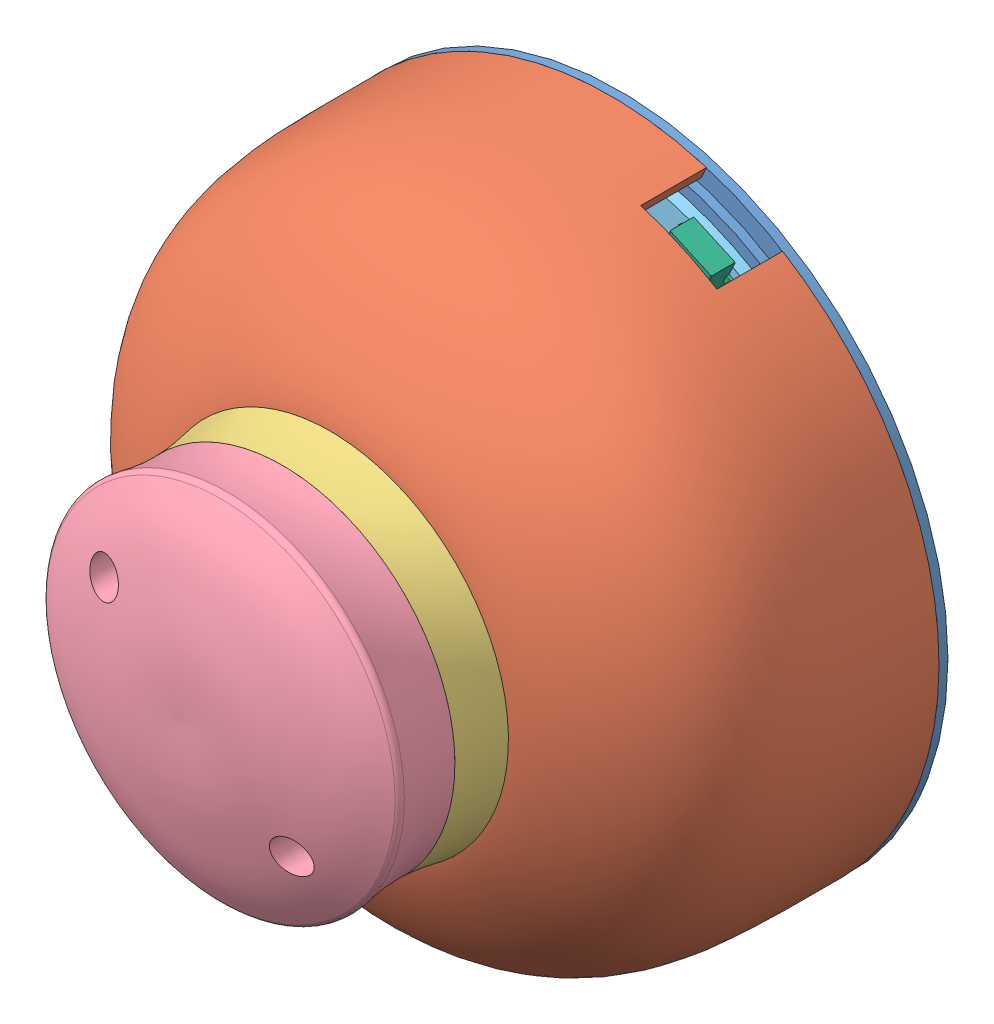
SolidWorks assembly 3DMaus, configuration Standard. Lengths in mm.
Overall size (148.65 148.65 73.92).
6 component instances, 6 part files, 13 mates.
Components (placement in the parent):
- bottom-1: bottom [Standard] at (-1.0972 12.3315 221.6557) x (0.915424 -0.40249 0) z (0 0 1) size (110 110 36)
- case-1: case [Standard] at (-1.0972 12.3315 223.1557) x (-0.40249 -0.915424 0) z (-0.915424 0.40249 0) size (112.79 47 112.79)
- KnobBottom-2: KnobBottom [Standard] at (-0.8007 12.0936 268.0568) x (0.625836 0.779955 0) z (0.779955 -0.625836 0) size (59.7 8 59.7)
- KnobTop-2: KnobTop [Standard] at (-0.8007 12.0936 268.0568) x (0.625836 0.779955 0) z (0.779955 -0.625836 0) size (59.45 17.42 59.45)
- pcb-1: pcb [Standard] at (-46.6842 32.8823 224.6557) x (0.911614 -0.411048 0) z (0 0 1) size (60 50.01 2)
- components-1: components [Standard] at (-46.6842 32.8823 226.6557) x (0.911614 -0.411048 0) z (0 0 1) size (43.52 48.07 4)
Mates (geometry in assembly coordinates):
- Deckungsgleich6: coincident anti-aligned: plane of pcb-1 through (-46.6842 32.8823 226.6557) normal (0 0 1); plane of components-1 through (-46.6842 32.8823 226.6557) normal (0 0 -1)
- Konzentrisch11: concentric aligned: circle of pcb-1; circle of components-1
- Konzentrisch12: concentric aligned: circle of pcb-1; circle of components-1
- Deckungsgleich7: coincident anti-aligned: plane of bottom-1 through (-1.0972 12.3315 224.6557) normal (0 0 1); plane of pcb-1 through (-46.6842 32.8823 224.6557) normal (0 0 -1)
- Konzentrisch13: concentric aligned: circle of bottom-1; circle of pcb-1
- Deckungsgleich15: coincident anti-aligned: plane of KnobBottom-2 through (-0.8007 12.0936 278.1557) normal (0 0 1); plane of KnobTop-2 through (-0.8007 12.0936 278.1557) normal (0 0 -1)
- Konzentrisch17: concentric aligned: circle of KnobBottom-2; circle of KnobTop-2
- Konzentrisch18: concentric aligned: circle of KnobBottom-2; circle of KnobTop-2
- Deckungsgleich18: coincident aligned: circle of bottom-1; circle of pcb-1
- Deckungsgleich19: coincident anti-aligned: circle of bottom-1; circle of case-1
- Konzentrisch19: concentric anti-aligned: circle of bottom-1; circle of case-1
- Deckungsgleich21: coincident anti-aligned: plane of case-1 through (-12.492 -13.5849 270.1557) normal (0 0 1); plane of KnobBottom-2 through (-0.8007 12.0936 270.1557) normal (0 0 -1)
- Konzentrisch20: concentric anti-aligned: circle of case-1; circle of KnobTop-2
